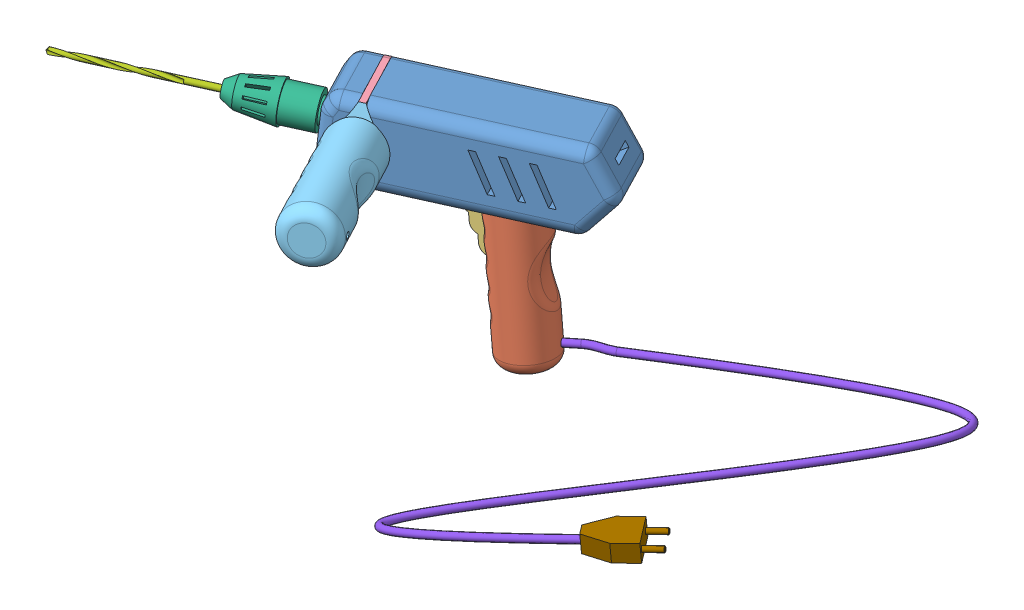
SolidWorks assembly PowerDrill, configuration Default. Lengths in mm.
Overall size (707.05 209.01 439.47).
9 component instances, 9 part files, 18 mates.
Components (placement in the parent):
- body-2: body [Default] at (72.9871 127.7914 136.1233) x (0.865483 -0.072857 -0.495613) z (0.500931 0.120407 0.857071) size (197.69 64.52 70)
- handle-2: handle [Default] at (119.1866 101.9555 154.307) x (0.852815 0.10017 -0.512517) z (0.147563 -0.987658 0.052507) size (45.68 45 121.93)
- triger-1: triger [Default] at (107.8799 58.4933 166.3019) x (-0.500931 -0.120407 -0.857071) z (0.852815 0.10017 -0.512517) size (15 44.12 15)
- support-1: support [Default] at (20.5089 102.1604 178.1462) x (0.865483 -0.072857 -0.495613) z (0.010644 0.991818 -0.127214) size (5 70 64.5)
- handle - support-1: handle - support [Default] at (54.6114 141.2794 232.4793) x (0.865483 -0.072857 -0.495613) z (0.500826 0.104826 0.859177) size (45.68 64.5 125)
- chalck-1: chalck [Default] at (27.3671 141.3491 210.114) x (0.865483 -0.072857 -0.495613) z (-0.190853 0.86679 -0.460706) size (88 32.58 32.58)
- drillbit-1: drillbit [Default] at (-148.4766 151.9997 302.9979) x (-0.054006 -0.997171 0.052277) z (0.498019 0.018479 0.866969) size (9.13 120.25 9.17)
- wire-2: wire [Default] at (134.5331 -0.7609 159.7677) x (0.18271 -0.976635 0.113144) z (-0.852815 -0.10017 0.512517) size (6 313.64 335.27)
- plug-1: plug [Default] at (414.7814 63.4916 337.557) x (0.610367 0.008979 0.792068) z (-0.066537 0.996983 0.039972) size (30 54.34 15)
Mates (geometry in assembly coordinates):
- Concentric3: concentric anti-aligned: cylinder of body-2 through (116.0675 122.8317 153.1972) axis (0.147563 -0.987658 0.052507) radius 7.3861; cylinder of handle-2 through (122.5805 79.2394 155.5147) axis (-0.147563 0.987658 -0.052507) radius 7.5
- Coincident1: coincident anti-aligned: plane of body-2 through (180.6752 98.5001 158.9715) normal (-0.002768 -0.990047 0.140707); plane of handle-2 through (137.6144 92.8772 118.5597) normal (0.002768 0.990047 -0.140707)
- Parallel2: parallel aligned: plane of body-2 through (72.9871 127.7914 136.1233) normal (-0.500931 -0.120407 -0.857071); plane of triger-1 through (104.1229 57.5902 159.8738) normal (-0.500931 -0.120407 -0.857071)
- Coincident4: coincident anti-aligned: plane of body-2 through (180.6752 98.5001 158.9715) normal (-0.002768 -0.990047 0.140707); plane of triger-1 through (92.6905 102.9804 188.7647) normal (0.002768 0.990047 -0.140707)
- Width1: width aligned: plane of body-2 through (72.9871 127.7914 136.1233) normal (-0.500931 -0.120407 -0.857071); plane of body-2 through (108.0523 136.2199 196.1183) normal (0.500931 0.120407 0.857071); plane of triger-1 through (104.1229 57.5902 159.8738) normal (-0.500931 -0.120407 -0.857071); plane of triger-1 through (111.6369 59.3963 172.7299) normal (0.500931 0.120407 0.857071)
- Distance2: distance = 90 mm: line of triger-1 through (84.8207 99.6598 165.2452) axis (0.500931 0.120407 0.857071); plane of body-2 through (28.2512 123.612 244.5309) normal (-0.865483 0.072857 0.495613)
- Concentric6: concentric aligned: cylinder of body-2 through (36.7367 136.4083 196.9368) axis (-0.865483 0.072857 0.495613) radius 10; cylinder of chalck-1 through (-27.309 141.7997 233.6121) axis (-0.865483 0.072857 0.495613) radius 10
- Distance3: distance = 5 mm anti-aligned: plane of chalck-1 through (1.8132 134.0251 206.9204) normal (0.865483 -0.072857 -0.495613); plane of body-2 through (28.2512 123.612 244.5309) normal (-0.865483 0.072857 0.495613)
- Concentric7: concentric anti-aligned: cylinder of chalck-1 through (-47.2151 143.4755 245.0112) axis (0.865483 -0.072857 -0.495613) radius 2.5; cylinder of drillbit-1 through (-44.6187 143.2569 243.5244) axis (-0.865483 0.072857 0.495613) radius 2.5
- Distance5: distance = 20 mm anti-aligned: plane of chalck-1 through (-29.7174 139.2345 229.7834) normal (-0.865483 0.072857 0.495613); plane of drillbit-1 through (-44.6187 143.2569 243.5244) normal (0.865483 -0.072857 -0.495613)
- Concentric11: concentric anti-aligned: cylinder of handle-2 through (228.3427 10.2578 103.3909) axis (-0.852815 -0.10017 0.512517) radius 3; cylinder of wire-2 through (134.5331 -0.7609 159.7677) axis (0.852815 0.10017 -0.512517) radius 3
- Coincident25: coincident anti-aligned: circle of handle-2; circle of wire-2
- Distance7: distance = 0 mm anti-aligned: plane of support-1 through (19.5564 165.2215 162.6994) normal (0.865483 -0.072857 -0.495613); plane of body-2 through (36.7367 136.4083 196.9368) normal (-0.865483 0.072857 0.495613)
- Concentric14: concentric anti-aligned: cylinder of body-2 through (32.4093 136.7726 199.4149) axis (0.865483 -0.072857 -0.495613) radius 21.9509; cylinder of support-1 through (41.0641 136.044 194.4588) axis (-0.865483 0.072857 0.495613) radius 21.9509
- Coincident28: coincident aligned: line of support-1 through (50.2868 172.9236 225.3198) axis (0.865483 -0.072857 -0.495613); line of handle - support-1 through (50.2868 172.9236 225.3198) axis (0.865483 -0.072857 -0.495613)
- Coincident29: coincident anti-aligned: plane of support-1 through (54.6142 172.5593 222.8418) normal (0.500826 0.104826 0.859177); plane of handle - support-1 through (50.2868 172.9236 225.3198) normal (-0.500826 -0.104826 -0.859177)
- Coincident30: coincident anti-aligned: line of support-1 through (50.2868 172.9236 225.3198) axis (-0.010644 -0.991818 0.127214); line of handle - support-1 through (49.6003 108.9513 233.5251) axis (0.010644 0.991818 -0.127214)
- Coincident31: coincident aligned: circle of wire-2; circle of plug-1
